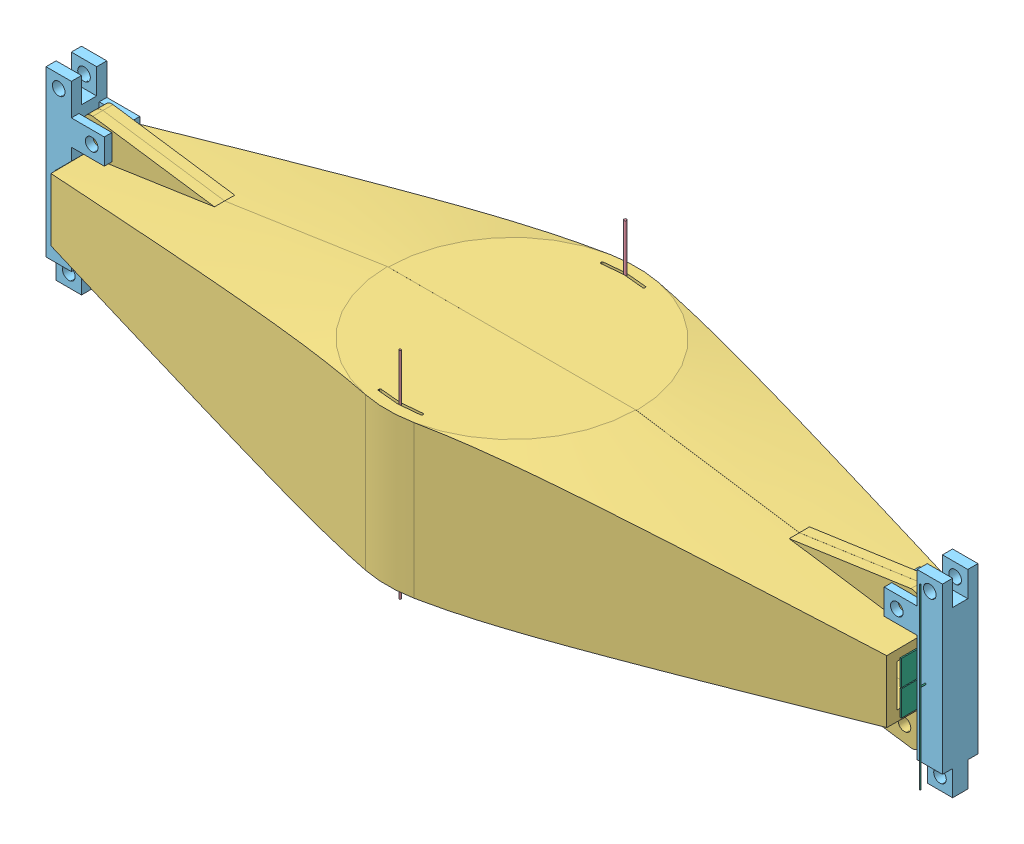
SolidWorks assembly RealUnit, configuration 默认. Lengths in mm.
Overall size (374.87 90.61 350.65).
11 component instances, 6 part files, 14 mates.
Components (placement in the parent):
- BEGeDet-1: BEGeDet [默认] at (2.9686 -23.0613 80) size (80 40 80)
- InnerShell-IV-1: InnerShell-IV [默认] at (2.9686 -23.1113 80) x (0.656103 0 0.754671) z (-0.754671 0 0.656103) size (89 50 89)
- RealOuterShell-IV-Part-3: RealOuterShell-IV-Part [默认] at (2.9686 -24.1113 80) x (-1 0 0) z (0 0 -1) size (357.21 73.56 262.25)
- RealOuterShell-IV-Part-4: RealOuterShell-IV-Part [默认] at (2.5967 -24.1114 80) x (1 0.000332 0) z (0 0 1) size (357.21 73.56 262.25)
- Electronics-1: Electronics [默认] at (2.9686 -48.2113 80) x (-1 0 0) z (0 0 -1) size (21.21 85 89.7)
- ConnectionUnit-1: ConnectionUnit [默认] at (157.8605 -24.8554 155) x (-1 -0.000332 0) z (0 0 -1) size (23 75 26.4)
  - ConnectionRod-IV-1: ConnectionRod-IV [默认] at (-16.742 6.238 75) size (23 75 14)
  - RealSiPMArray-1: RealSiPMArray [默认] at (-11.242 1.238 75) x (-1 0 0) z (0 0 -1) size (3.97 70 26.4)
- ConnectionUnit-2: ConnectionUnit [默认] at (-152.295 -24.9069 5) size (23 75 26.4)
  - ConnectionRod-IV-1: ConnectionRod-IV [默认] at (-16.742 6.238 75) size (23 75 14)
  - RealSiPMArray-1: RealSiPMArray [默认] at (-11.242 1.238 75) x (-1 0 0) z (0 0 -1) size (3.97 70 26.4)
Mates (geometry in assembly coordinates):
- 重合1: coincident anti-aligned: plane of BEGeDet-1 through (2.9686 -3.0613 80) normal (0 1 0); plane of InnerShell-IV-1 through (2.9686 -3.0613 80) normal (0 -1 0)
- 同心1: concentric aligned: circle of BEGeDet-1; circle of InnerShell-IV-1
- 重合5: coincident anti-aligned: circle of RealOuterShell-IV-Part-3; circle of RealOuterShell-IV-Part-4
- 重合6: coincident anti-aligned: circle of RealOuterShell-IV-Part-3; circle of RealOuterShell-IV-Part-4
- 同心14: concentric anti-aligned: circle of BEGeDet-1; circle of Electronics-1
- 重合10: coincident anti-aligned: plane of InnerShell-IV-1 through (2.9686 -48.1113 80) normal (0 -1 0); plane of Electronics-1 through (2.9686 -48.1113 60.201) normal (0 1 0)
- 同心15: concentric anti-aligned: circle of InnerShell-IV-1; circle of RealOuterShell-IV-Part-3
- 重合11: coincident anti-aligned: circle of InnerShell-IV-1; plane of RealOuterShell-IV-Part-3 through (2.9686 1.8887 80) normal (0 -1 0)
- 垂直1: perpendicular: line of RealOuterShell-IV-Part-3 through (51.9686 -54.1113 80) axis (-1 0 0); line of Electronics-1 through (2.7686 -48.6113 80) axis (0 0 1)
- 重合13: coincident aligned: circle of RealOuterShell-IV-Part-4; circle of ConnectionUnit-2/ConnectionRod-IV-1
- 平行3: parallel aligned: plane of RealOuterShell-IV-Part-3 through (-162.0314 -66.2676 96.9895) normal (-1 0 0); plane of ConnectionUnit-2/ConnectionRod-IV-1 through (-174.037 13.8311 73) normal (-1 0 0)
- 重合15: coincident anti-aligned: circle of RealOuterShell-IV-Part-4; circle of ConnectionUnit-1/ConnectionRod-IV-1
- 平行4: parallel aligned: plane of RealOuterShell-IV-Part-4 through (167.6107 -66.2128 63.0105) normal (1 0.000332 0); plane of ConnectionUnit-1/ConnectionRod-IV-1 through (179.5896 13.8899 87) normal (1 0.000332 0)
- 平行5: parallel anti-aligned: line of BEGeDet-1 through (2.9686 -43.0613 80) axis (1 0 0); line of RealOuterShell-IV-Part-3 through (51.9686 -54.1113 80) axis (-1 0 0)
